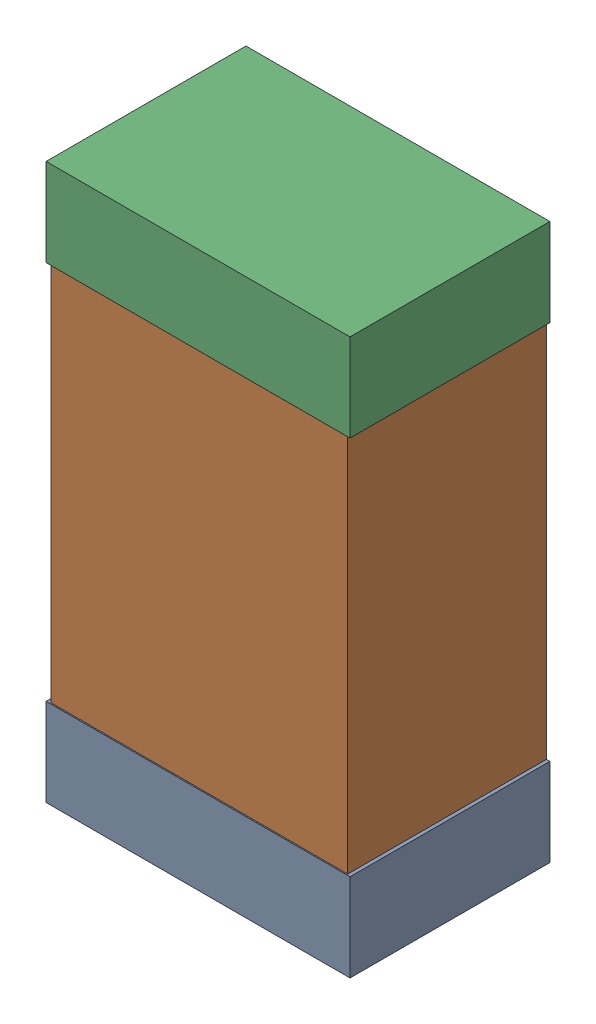
SolidWorks assembly Kanaloa_v2.0.0_Power_6, configuration Default. Lengths in mm.
Overall size (1.3 2.38 0.85).
6 component instances, 2 part files, 0 mates.
Components (placement in the parent):
- 330415056-1: 330415056 [Default] at (129.2818 84.1244 0) size (1.3 0.38 0.85)
  - Extruded_2-1: Extruded_2 [Default] at origin size (1.3 0.38 0.85)
- 334787376-1: 334787376 [Default] at (129.2818 85.1244 0) size (1.27 2.2 0.85)
  - Extruded_16-1: Extruded_16 [Default] at origin size (1.27 2.2 0.85)
- 330415056-2: 330415056 [Default] at (129.2818 86.1244 0) size (1.3 0.38 0.85)
  - Extruded_2-1: Extruded_2 [Default] at origin size (1.3 0.38 0.85)
